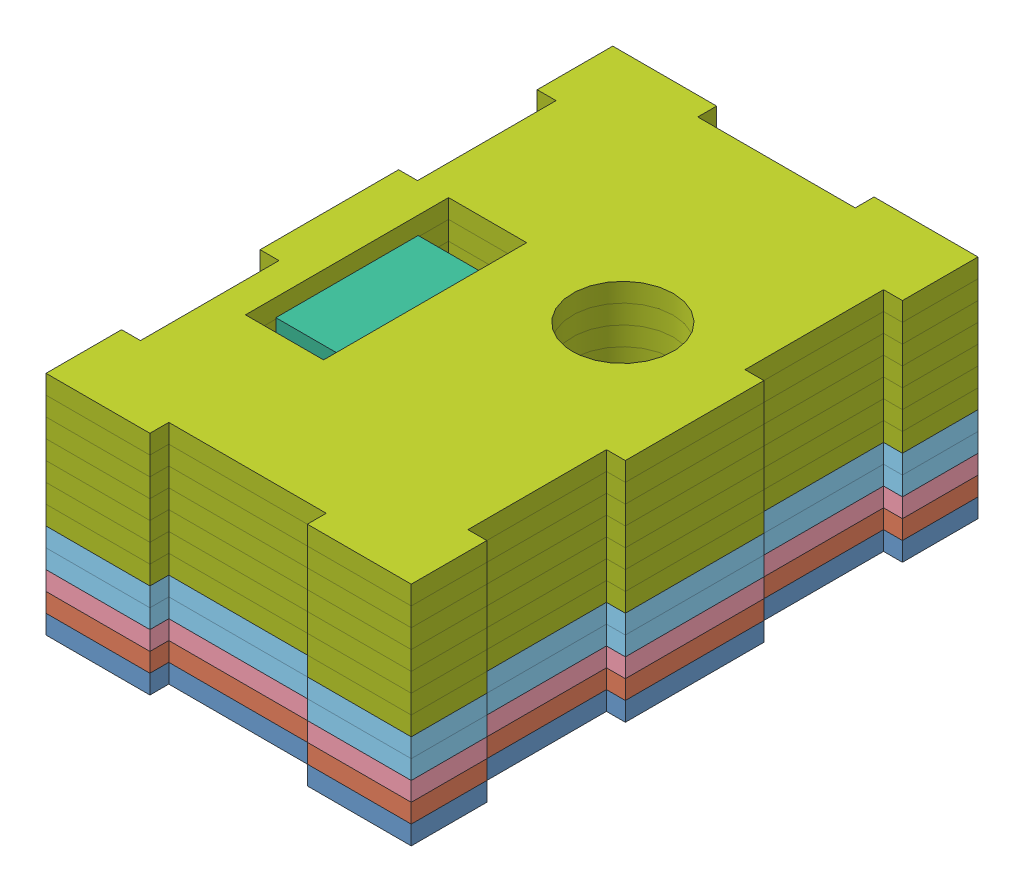
SolidWorks assembly Assembly, configuration Default. Lengths in mm.
Overall size (67.72 36 90).
14 component instances, 7 part files, 20 mates.
Components (placement in the parent):
- 1st-1: 1st [Default] at (28.2415 50.1374 22.1514) size (58 3 90)
- 2nd-3: 2nd [Default] at (28.2415 53.1374 22.1514) size (58 3 90)
- pusher-1: pusher [Default] at (57.126 53.1374 44.8476) x (0.688927 0 0.72483) z (-0.72483 0 0.688927) size (44.2 3 44.2)
- 3rd-1: 3rd [Default] at (28.2415 56.1374 22.1514) size (58 3 90)
- 4th-1: 4th [Default] at (28.2415 59.1374 22.1514) size (58 3 90)
- Servo-1: Servo [Varsayılan] at (16.2415 83.3374 72.1514) x (-1 0 0) z (0 0 1) size (12.4 30 32.25)
- 4th-2: 4th [Default] at (28.2415 62.1374 22.1514) size (58 3 90)
- 5th-1: 5th [Default] at (28.2415 65.1374 22.1514) size (58 3 90)
- 5th-2: 5th [Default] at (28.2415 68.1374 22.1514) size (58 3 90)
- 5th-3: 5th [Default] at (28.2415 71.1374 22.1514) size (58 3 90)
- 5th-4: 5th [Default] at (28.2415 74.1374 22.1514) size (58 3 90)
- 5th-5: 5th [Default] at (28.2415 77.1374 22.1514) size (58 3 90)
- 5th-6: 5th [Default] at (28.2415 80.1374 22.1514) size (58 3 90)
- 5th-7: 5th [Default] at (28.2415 83.1374 22.1514) size (58 3 90)
Mates (geometry in assembly coordinates):
- Coincident8: coincident: plane of 1st-1 through (28.2415 53.1374 22.1514) normal (0 1 0); plane of 2nd-3 through (28.2415 53.1374 22.1514) normal (0 -1 0)
- Coincident9: coincident: point of 1st-1; point of 2nd-3
- Coincident10: coincident: point of 1st-1; point of 2nd-3
- Coincident12: coincident: plane of 1st-1 through (28.2415 53.1374 22.1514) normal (0 1 0); plane of pusher-1 through (16.2415 53.1374 67.1514) normal (0 -1 0)
- Coincident13: coincident: plane of 2nd-3 through (28.2415 56.1374 22.1514) normal (0 1 0); plane of 3rd-1 through (28.2415 56.1374 22.1514) normal (0 -1 0)
- Coincident14: coincident: point of 2nd-3; point of 3rd-1
- Coincident15: coincident: point of 2nd-3; point of 3rd-1
- Coincident16: coincident: plane of 3rd-1 through (28.2415 59.1374 22.1514) normal (0 1 0); plane of 4th-1 through (28.2415 59.1374 22.1514) normal (0 -1 0)
- Coincident17: coincident: point of 3rd-1; point of 4th-1
- Coincident18: coincident: point of 3rd-1; point of 4th-1
- Coincident21: coincident: plane of Servo-1 through (16.2415 68.1374 72.1514) normal (0 -1 0); plane of 5th-1 through (28.2415 68.1374 22.1514) normal (0 1 0)
- Coincident22: coincident: point of Servo-1; point of 5th-1
- Coincident23: coincident: point of Servo-1; point of 5th-1
- Concentric2: concentric: circle of 1st-1; circle of pusher-1
- Coincident26: coincident: plane of Servo-1 through (16.2415 65.1374 72.1514) normal (0 -1 0); plane of 4th-2 through (28.2415 65.1374 22.1514) normal (0 1 0)
- Coincident27: coincident: point of Servo-1; point of 4th-2
- Parallel1: parallel: line of Servo-1 through (10.0415 83.3374 83.4514) axis (0 0 -1); line of 4th-2 through (2.2415 65.1374 56.1514) axis (0 0 1)
- Coincident29: coincident: plane of 4th-2 through (28.2415 65.1374 22.1514) normal (0 1 0); plane of 5th-1 through (28.2415 65.1374 22.1514) normal (0 -1 0)
- Coincident30: coincident: point of 4th-2; point of 5th-1
- Coincident31: coincident: point of 4th-2; point of 5th-1
